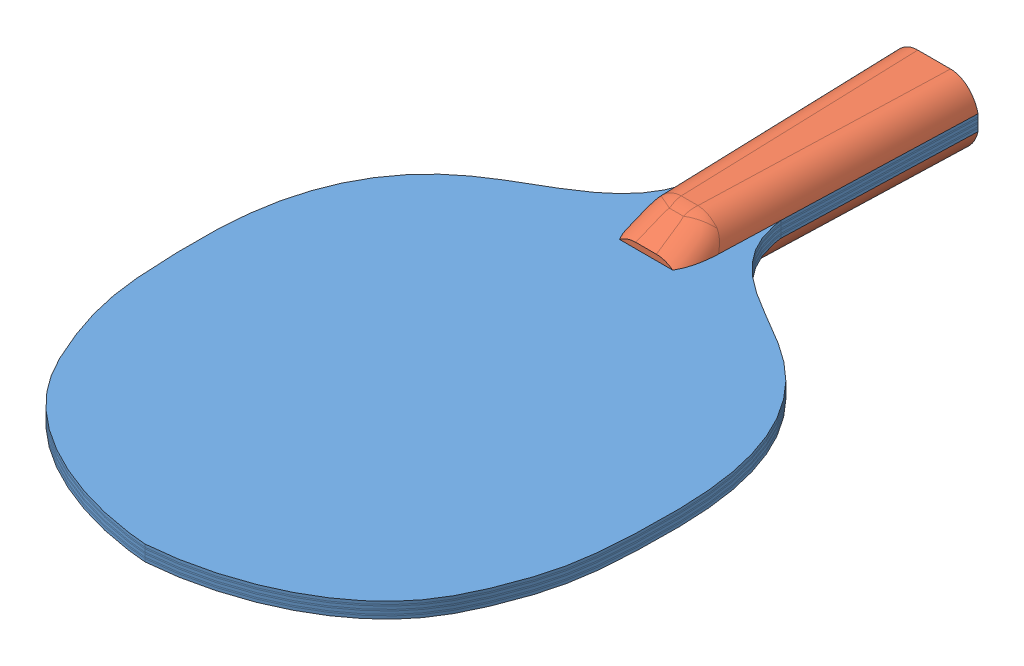
SolidWorks assembly pingpongPaddle, configuration Default. Lengths in mm.
Overall size (151.49 21.04 252.78).
9 component instances, 2 part files, 6 mates.
Components (placement in the parent):
- shell_-1: shell_ [wood_1] at (88.5011 176.7632 165.6213) size (151.49 0.9 252)
- shell_-2: shell_ [cotton_shell] at (88.5011 177.6632 165.6213) size (151.49 0.45 252)
- shell_-3: shell_ [wood_2] at (88.5011 178.1132 165.6213) size (151.49 0.9 252)
- shell_-4: shell_ [cotton_shell] at (88.5011 179.0132 165.6213) size (151.49 0.45 252)
- shell_-5: shell_ [wood_2] at (88.5011 179.4632 165.6213) size (151.49 0.9 252)
- shell_-6: shell_ [cotton_shell] at (88.5011 180.3632 165.6213) size (151.49 0.45 252)
- shell_-7: shell_ [wood_1] at (88.5011 180.8132 165.6213) size (151.49 0.9 252)
- hande_parts-3: hande_parts [handle] at (331.2358 181.7132 185.2523) size (28.09 8.54 92.78)
- hande_parts-4: hande_parts [handle] at (-154.2336 176.7632 185.2523) x (-1 0 0) z (0 0 1) size (28.09 8.54 92.78)
Mates (geometry in assembly coordinates):
- Coincident1: coincident: point of shell_-1; point of shell_-2
- Coincident2: coincident: point of shell_-2; point of shell_-3
- Coincident3: coincident: point of shell_-3; point of shell_-4
- Coincident4: coincident: point of shell_-4; point of shell_-5
- Coincident5: coincident: point of shell_-5; point of shell_-6
- Coincident6: coincident: point of shell_-6; point of shell_-7
